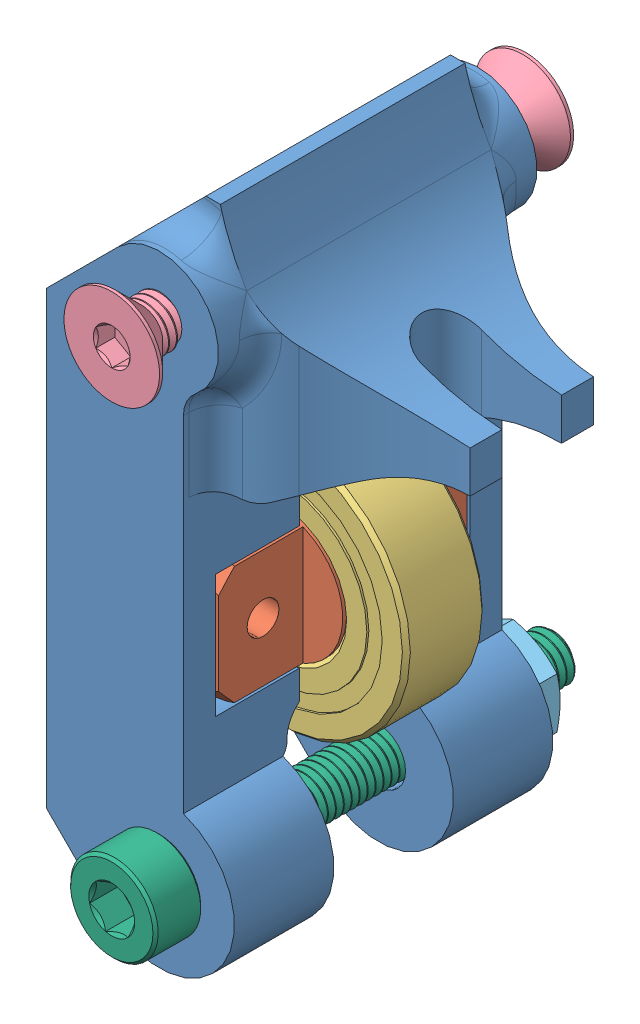
SolidWorks assembly Idler, configuration Default. Lengths in mm.
Overall size (16 41.13 28.26).
7 component instances, 6 part files, 14 mates.
Components (placement in the parent):
- IdlerBlock-1: IdlerBlock [Default] at origin size (12.3 41.13 20)
- IdlerPin-15mm-1: IdlerPin-15mm [Default] at origin size (7.5 8 15.6)
- Bearing-688-1: Bearing-688 [7804K117] at origin size (16 16 5)
- M3x12HexFlatScrew-1: M3x12HexFlatScrew [92125A132] at (0 18 13) size (6 6 12.31)
- M3x12HexFlatScrew-2: M3x12HexFlatScrew [92125A132] at (0 18.0007 -13) x (1 0 0) z (0 0 -1) size (6 6 12.31)
- M3HexNut-1: M3HexNut [90591A121] at (0 -12.6 -11.2) x (1 0 0) z (0 -1 0) size (5.5 2.58 6.35)
- M3x25-1: M3x25 [91290A125] at (0 -12.6 -15) x (-0.963337 0.268295 0) z (0 0 -1) size (5.5 5.5 28.26)
Mates (geometry in assembly coordinates):
- Coincident1: coincident aligned: plane of IdlerBlock-1 through (0 0 0) normal (0 0 1); plane of assembly through (0 0 0) normal (0 0 1)
- Coincident2: coincident aligned: plane of IdlerBlock-1 through (0 0 0) normal (0 1 0); plane of assembly through (0 0 0) normal (0 1 0)
- Coincident3: coincident aligned: plane of IdlerBlock-1 through (0 0 0) normal (1 0 0); plane of assembly through (0 0 0) normal (1 0 0)
- Coincident4: coincident aligned: plane of IdlerBlock-1 through (0 0 0) normal (0 0 1); plane of IdlerPin-15mm-1 through (0 0 0) normal (0 0 1)
- Concentric1: concentric anti-aligned: cylinder of IdlerBlock-1 through (0 0 8) axis (0 0 -1) radius 4.15; cylinder of IdlerPin-15mm-1 through (0 0 -7.8) axis (0 0 1) radius 4
- Parallel1: parallel aligned: plane of IdlerBlock-1 through (1.5 0 -10) normal (1 0 0); plane of IdlerPin-15mm-1 through (1.5 0 -7.8) normal (1 0 0)
- Coincident6: coincident aligned: plane of IdlerBlock-1 through (0 0 0) normal (0 0 1); plane of Bearing-688-1 through (0 0 0) normal (0 0 1)
- Concentric2: concentric aligned: cylinder of IdlerPin-15mm-1 through (0 0 -7.8) axis (0 0 1) radius 4; cylinder of Bearing-688-1 through (0 0 2.5) axis (0 0 1) radius 4
- Distance1: distance = 1 mm anti-aligned: plane of M3x12HexFlatScrew-1 through (0 16.5 1) normal (0 0 -1); plane of assembly through (0 0 0) normal (0 0 1)
- Concentric3: concentric aligned: cylinder of IdlerBlock-1 through (0 18 -10) axis (0 0 1) radius 1.2; circle of M3x12HexFlatScrew-1
- Concentric4: concentric anti-aligned: cylinder of IdlerBlock-1 through (0 -12.6 -10) axis (0 0 1) radius 1.7; cylinder of M3x25-1 through (0 -12.6 10) axis (0 0 -1) radius 1.5
- Coincident8: coincident anti-aligned: plane of IdlerBlock-1 through (0 0 10) normal (0 0 1); plane of M3x25-1 through (0 -12.6 10) normal (0 0 -1)
- Coincident9: coincident anti-aligned: plane of IdlerBlock-1 through (0 0 -10) normal (0 0 -1); plane of M3HexNut-1 through (2.75 -11.0123 -10) normal (0 0 1)
- Concentric5: concentric aligned: circle of M3HexNut-1; cylinder of M3x25-1 through (0 -12.6 10) axis (0 0 -1) radius 1.5
